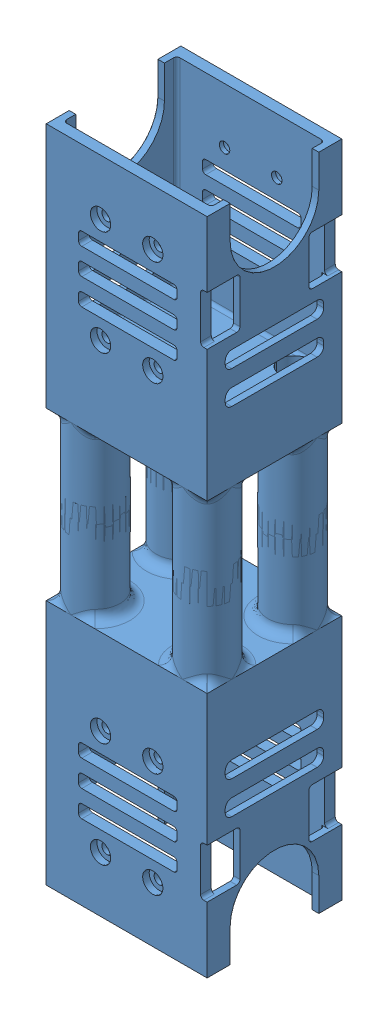
SolidWorks assembly thigh540540latest, configuration Default. Lengths in mm.
Overall size (49 200.74 41).
2 component instances, 1 part files, 2 mates.
Components (placement in the parent):
- x540conntoptri-1: x540conntoptri [Default] at (78.8172 29.2967 96.5919) x (0 -1 0) z (0 0 1) size (105 49 41)
- x540conntoptri-2: x540conntoptri [Default] at (78.8172 180.0375 137.5919) x (0 1 0) z (0 0 -1) size (105 49 41)
Mates (geometry in assembly coordinates):
- Coincident1: coincident aligned: plane of x540conntoptri-1 through (54.3172 59.2967 137.5919) normal (-1 0 0); plane of x540conntoptri-2 through (54.3172 150.0375 96.5919) normal (-1 0 0)
- Coincident2: coincident aligned: plane of x540conntoptri-1 through (78.8172 29.2967 96.5919) normal (0 0 -1); plane of x540conntoptri-2 through (78.8172 180.0375 96.5919) normal (0 0 -1)
